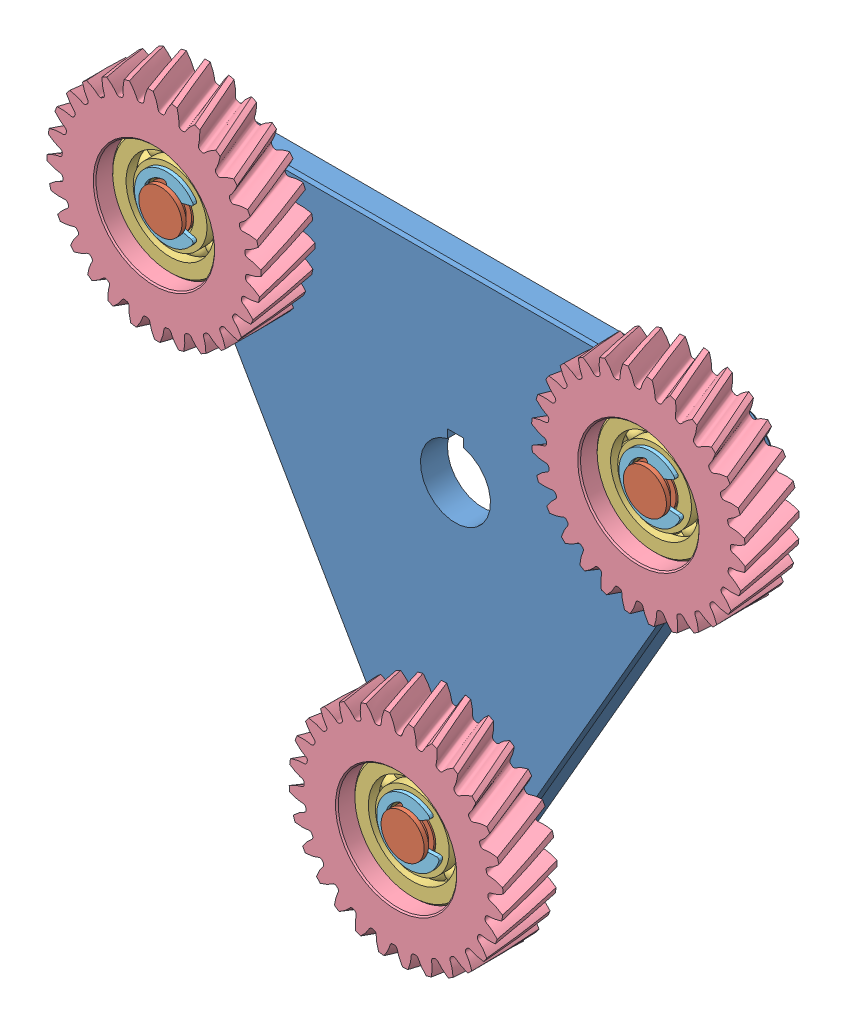
SolidWorks assembly Planet_Assembly, configuration Default. Lengths in mm.
Overall size (139.89 132.49 16).
13 component instances, 5 part files, 25 mates.
Components (placement in the parent):
- Carrier-1: Carrier [Default] at (7.7308 72.6245 98.192) size (109.53 97 5)
- planetshaftMECH360-1: planetshaftMECH360 [Default] at (-37.1986 98.5645 99.192) size (13 13 14.8)
- planetshaftMECH360-2: planetshaftMECH360 [Default] at (7.7308 20.7445 99.192) x (0.987351 0.158553 0) z (0 0 1) size (13 13 14.8)
- planetshaftMECH360-4: planetshaftMECH360 [Default] at (52.6602 98.5645 99.192) x (0.959125 0.282984 0) z (0 0 1) size (13 13 14.8)
- Planet Bearing-10: Planet Bearing [5972K91] at (52.6602 98.5645 102.692) size (22 22 7)
- Planet Bearing-11: Planet Bearing [5972K91] at (7.7308 20.7445 102.692) x (0.987351 0.158553 0) z (0 0 1) size (22 22 7)
- Planet Bearing-13: Planet Bearing [5972K91] at (-37.1986 98.5645 102.692) x (0.959125 0.282984 0) z (0 0 1) size (22 22 7)
- Planet 28t-6: Planet 28t [Planet_Revolving_Follower01] at (52.6602 98.5645 104.192) x (0.794137 0.607739 0) z (0 0 -1) size (40.37 40.37 10)
- Planet 28t-3: Planet 28t [Planet_Revolving_Follower01] at (-37.1986 98.5645 104.192) x (0.080364 0.996766 0) z (0 0 1) size (40.37 40.37 10)
- Planet 28t-5: Planet 28t [Planet_Revolving_Follower01] at (7.7308 20.7445 104.192) x (-0.923718 -0.383074 0) z (0 0 -1) size (40.37 40.37 10)
- 98543A114_SIDE-MOUNT EXTERNAL RETAINING RING  E-STYLE-1: 98543A114_SIDE-MOUNT EXTERNAL RETAINING RING  E-STYLE [98543A114] at (-37.1986 98.5645 106.542) x (0 0 -1) z (1 0 0) size (0.7 11.8 10.84)
- 98543A114_SIDE-MOUNT EXTERNAL RETAINING RING  E-STYLE-2: 98543A114_SIDE-MOUNT EXTERNAL RETAINING RING  E-STYLE [98543A114] at (52.6602 98.5645 106.542) x (0 0 -1) z (0.987351 0.158553 0) size (0.7 11.8 10.84)
- 98543A114_SIDE-MOUNT EXTERNAL RETAINING RING  E-STYLE-4: 98543A114_SIDE-MOUNT EXTERNAL RETAINING RING  E-STYLE [98543A114] at (7.7308 20.7445 106.542) x (0 0 -1) z (0.959125 0.282984 0) size (0.7 11.8 10.84)
Mates (geometry in assembly coordinates):
- Concentric1: concentric aligned: cylinder of Carrier-1 through (-37.1986 98.5645 93.192) axis (0 0 1) radius 6.5; cylinder of planetshaftMECH360-1 through (-37.1986 98.5645 93.192) axis (0 0 1) radius 6.5
- Coincident1: coincident aligned: plane of Carrier-1 through (-39.0345 99.6245 93.192) normal (0 0 -1); plane of planetshaftMECH360-1 through (-37.1986 98.5645 93.192) normal (0 0 -1)
- Concentric2: concentric aligned: cylinder of Carrier-1 through (7.7308 20.7445 93.192) axis (0 0 1) radius 6.5; cylinder of planetshaftMECH360-2 through (7.7308 20.7445 93.192) axis (0 0 1) radius 6.5
- Coincident2: coincident aligned: plane of Carrier-1 through (-39.0345 99.6245 93.192) normal (0 0 -1); plane of planetshaftMECH360-2 through (7.7308 20.7445 93.192) normal (0 0 -1)
- Concentric3: concentric aligned: cylinder of Carrier-1 through (52.6602 98.5645 93.192) axis (0 0 1) radius 6.5; cylinder of planetshaftMECH360-4 through (52.6602 98.5645 93.192) axis (0 0 1) radius 6.5
- Coincident3: coincident aligned: plane of Carrier-1 through (-39.0345 99.6245 93.192) normal (0 0 -1); plane of planetshaftMECH360-4 through (52.6602 98.5645 93.192) normal (0 0 -1)
- Concentric8: concentric anti-aligned: cylinder of planetshaftMECH360-4 through (52.6602 98.5645 107.992) axis (0 0 -1) radius 4; cylinder of Planet Bearing-10 through (52.6602 98.5645 106.192) axis (0 0 1) radius 4
- Coincident8: coincident anti-aligned: plane of planetshaftMECH360-4 through (52.6602 98.5645 99.192) normal (0 0 1); plane of Planet Bearing-10 through (52.6602 102.9145 99.192) normal (0 0 -1)
- Concentric9: concentric anti-aligned: cylinder of planetshaftMECH360-2 through (7.7308 20.7445 107.992) axis (0 0 -1) radius 4; cylinder of Planet Bearing-11 through (7.7308 20.7445 106.192) axis (0 0 1) radius 4
- Coincident9: coincident anti-aligned: plane of planetshaftMECH360-2 through (7.7308 20.7445 99.192) normal (0 0 1); plane of Planet Bearing-11 through (7.0411 25.0394 99.192) normal (0 0 -1)
- Concentric10: concentric anti-aligned: cylinder of planetshaftMECH360-1 through (-37.1986 98.5645 107.992) axis (0 0 -1) radius 4; cylinder of Planet Bearing-13 through (-37.1986 98.5645 106.192) axis (0 0 1) radius 4
- Coincident10: coincident anti-aligned: plane of planetshaftMECH360-1 through (-37.1986 98.5645 99.192) normal (0 0 1); plane of Planet Bearing-13 through (-38.4296 102.7367 99.192) normal (0 0 -1)
- Concentric11: concentric anti-aligned: cylinder of Planet Bearing-10 through (52.6602 98.5645 106.192) axis (0 0 1) radius 11; cylinder of Planet 28t-6 through (52.6602 98.5645 104.192) axis (0 0 -1) radius 11
- Concentric13: concentric aligned: cylinder of Planet Bearing-13 through (-37.1986 98.5645 106.192) axis (0 0 1) radius 11; cylinder of Planet 28t-3 through (-37.1986 98.5645 104.192) axis (0 0 1) radius 11
- Concentric14: concentric anti-aligned: cylinder of Planet Bearing-11 through (7.7308 20.7445 106.192) axis (0 0 1) radius 11; cylinder of Planet 28t-5 through (7.7308 20.7445 104.192) axis (0 0 -1) radius 11
- Concentric16: concentric anti-aligned: cylinder of planetshaftMECH360-1 through (-37.1986 98.5645 107.992) axis (0 0 -1) radius 4; cylinder of 98543A114_SIDE-MOUNT EXTERNAL RETAINING RING  E-STYLE-1 through (-37.1986 98.5645 106.192) axis (0 0 1) radius 5.9
- Coincident15: coincident anti-aligned: plane of planetshaftMECH360-1 through (-37.1986 98.5645 106.192) normal (0 0 1); plane of 98543A114_SIDE-MOUNT EXTERNAL RETAINING RING  E-STYLE-1 through (-37.1986 98.5645 106.192) normal (0 0 -1)
- Concentric17: concentric anti-aligned: cylinder of planetshaftMECH360-4 through (52.6602 98.5645 107.992) axis (0 0 -1) radius 4; cylinder of 98543A114_SIDE-MOUNT EXTERNAL RETAINING RING  E-STYLE-2 through (52.6602 98.5645 106.192) axis (0 0 1) radius 5.9
- Coincident16: coincident anti-aligned: plane of planetshaftMECH360-4 through (52.6602 98.5645 106.192) normal (0 0 1); plane of 98543A114_SIDE-MOUNT EXTERNAL RETAINING RING  E-STYLE-2 through (52.6602 98.5645 106.192) normal (0 0 -1)
- Concentric18: concentric anti-aligned: cylinder of planetshaftMECH360-2 through (7.7308 20.7445 107.992) axis (0 0 -1) radius 4; cylinder of 98543A114_SIDE-MOUNT EXTERNAL RETAINING RING  E-STYLE-4 through (7.7308 20.7445 106.192) axis (0 0 1) radius 5.9
- Coincident17: coincident anti-aligned: plane of planetshaftMECH360-2 through (7.7308 20.7445 106.192) normal (0 0 1); plane of 98543A114_SIDE-MOUNT EXTERNAL RETAINING RING  E-STYLE-4 through (7.7308 20.7445 106.192) normal (0 0 -1)
- Coincident18: coincident aligned: plane of Planet Bearing-13 through (-40.2124 108.7791 99.192) normal (0 0 -1); plane of Planet 28t-3 through (-57.0074 100.1615 99.192) normal (0 0 -1)
- Coincident19: coincident aligned: plane of Planet Bearing-11 through (6.0422 31.2597 99.192) normal (0 0 -1); plane of Planet 28t-5 through (7.7308 20.7445 99.192) normal (0 0 -1)
- Coincident20: coincident aligned: plane of Planet Bearing-10 through (52.6602 109.2145 99.192) normal (0 0 -1); plane of Planet 28t-6 through (52.6602 98.5645 99.192) normal (0 0 -1)
- Coincident21: coincident aligned: plane of Planet Bearing-13 through (-40.2124 108.7791 99.192) normal (0 0 -1); plane of Planet 28t-3 through (-57.0074 100.1615 99.192) normal (0 0 -1)
